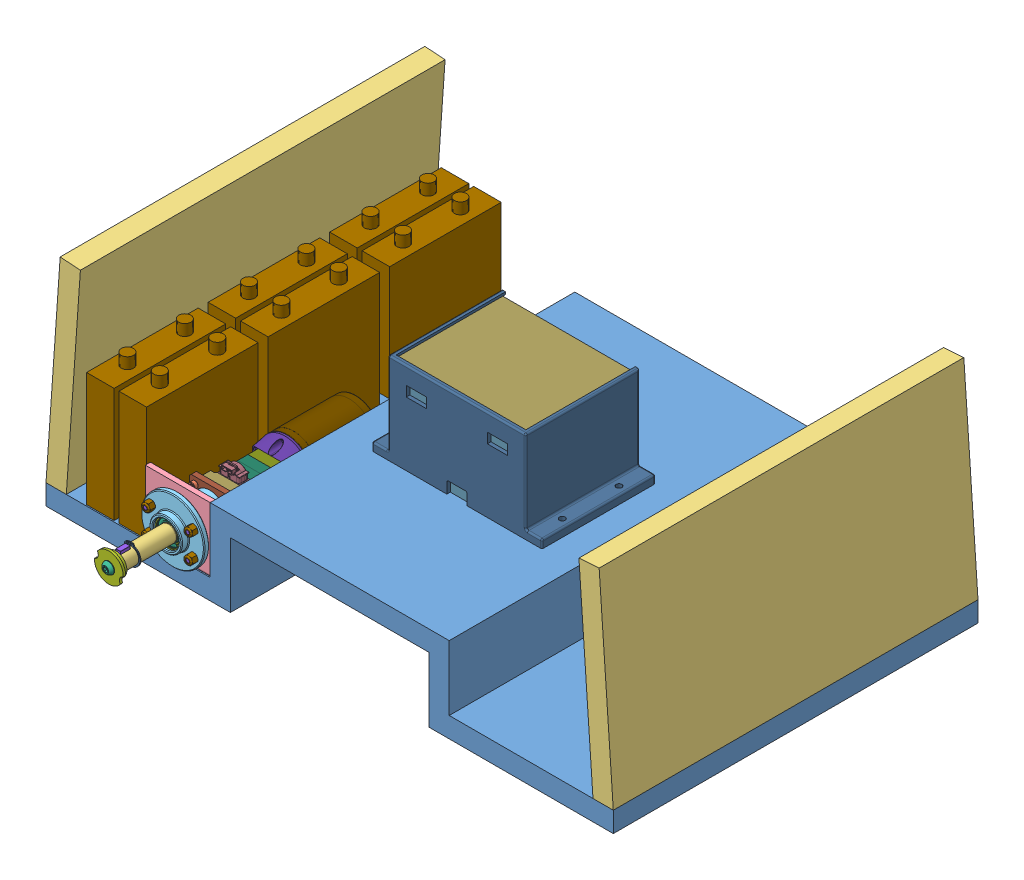
SolidWorks assembly ROVER_config2_batteries 2x3_verticales, configuration Default. Lengths in mm.
Overall size (700 275 569.67).
75 component instances, 32 part files, 13 mates.
Components (placement in the parent):
- Plancher-1: Plancher [Default] at (-314.6501 422.5882 577.2661) size (700 105 450)
- 01-Anneau_separation-1: 01-Anneau_separation [Default] at (38.152 502.5882 794.9914) x (0.982803 0 -0.184657) z (-0.184657 0 -0.982803) size (228.6 10 228.6)
- Mur_largeur-1: Mur_largeur [Default] at (-314.6501 447.5882 577.2661) size (42.42 250 450)
- Mur_largeur-2: Mur_largeur [Default] at (385.3499 447.5882 1027.2661) x (-1 0 0) z (0 0 -1) size (42.42 250 450)
- PB2023-M054 DRIVETRAIN ASSEMBLY-1: PB2023-M054 DRIVETRAIN ASSEMBLY [Default] at (-152.1501 480.5882 991.7661) x (0 1 0) z (0 0 1) size (93.83 80 344.65)
  - A12220103_FRONT_BRACKET_ASSEMBLY-1: A12220103_FRONT_BRACKET_ASSEMBLY [Default] at origin size (86 80 534.65)
    - 12220105_SUPPORT_BRACKET-1: 12220105_SUPPORT_BRACKET [Default] at (-52 -128.9256 -192.9876) x (0 0 -1) z (1 0 0) size (160.65 80 80)
    - A12220101_FRONT_CASE_ASSEMBLY-1: A12220101_FRONT_CASE_ASSEMBLY [Default] at origin size (78 78 141.2)
      - 12220103_FRONT_HOUSING-1: 12220103_FRONT_HOUSING [Default] at (-52 141.0744 -192.9876) x (0 0 -1) z (1 0 0) size (60 78 78)
      - BALL BEARING-1: BALL BEARING [6656K203] at origin size (32 32 10)
      - BALL BEARING-2: BALL BEARING [6656K203] at (0 0 41) size (32 32 10)
      - Internal Retaining Ring (98455A129)-1: Internal Retaining Ring (98455A129) [98455A129] at (0.0361 0.7992 46) x (0.998982 -0.045107 0) z (0 0 1) size (34.4 33.81 1.2)
    - M6 x 20mm Steel Hex Head Screw (91310A333)-2: M6 x 20mm Steel Hex Head Screw (91310A333) [91310A333] at (-15.125 -26.1973 37.15) x (0 0 1) z (-0.44141 0.897306 0) size (24.4 11.55 10)
    - M6 x 1mm Steel Hex LockNut (90592A016)-1: M6 x 1mm Steel Hex LockNut (90592A016) [97260A101] at (15.125 -26.1973 41.85) x (0.928554 -0.371196 0) z (-0.371196 -0.928554 0) size (10 8.38 11.55)
    - 20MM External Retaining Ring (98541A123)-4: 20MM External Retaining Ring (98541A123) [98541A123] at (0 0 92.94) x (0 0 1) z (-0.186581 0.98244 0) size (1.2 25.1 22.76)
    - A12220110_FRONT_SHAFT_ASSEMBLY-1: A12220110_FRONT_SHAFT_ASSEMBLY [Default] at (1.7896 0 -19.01) x (0 -1 0) z (0 0 1) size (78 67.32 307.03)
      - A12220105_MOTOR_BRACKET_ASSEMBLY-1: A12220105_MOTOR_BRACKET_ASSEMBLY [Default] at origin size (78 67.32 280.24) (flexible)
        - 12220106_MOTOR_BRACKET-1: 12220106_MOTOR_BRACKET [Default] at (0 -2.2046 8.53) size (78 52.48 69.85)
        - 12220106-051 MiniCIM Motor Assembly-1: 12220106-051 MiniCIM Motor Assembly [Default] at origin size (64.01 67.32 218.97)
          - Gearbox Assembly-1: Gearbox Assembly [Default] at (34.0244 -12.4567 -92.7758) x (0 0 1) z (-1 0 0) size (123.35 56.32 44.45)
            - Output Housing-2: Output Housing [Default] at (64.8023 -0.856 18.2213) x (1 0 0) z (0 -1 0) size (75.7 44.45 56.32)
              - Housing-1: Housing [Default] at (19.8785 -6.4219 -11.5232) size (18.13 44.45 42)
              - Encoder.step-1: Encoder.step [Default] at (12.6785 15.8031 -11.5232) x (0 0 1) z (-1 0 0) size (56.32 42 21.21)
              - Gearbox_output_shaft-1: Gearbox_output_shaft [Default] at origin size (63.51 17 17)
            - Ring Gears-1: Ring Gears [Default] at (71.9808 10.6671 11.7994) x (1 0 0) z (0 -1 0) size (32.2 42 42)
            - Ring Gear Stage 3-1: Ring Gear Stage 3 [Default] at (59.2808 10.6671 11.7994) x (1 0 0) z (0 -1 0) size (28.65 42 42)
          - CIM Adaptor.step-1: CIM Adaptor.step [Default] at (0 -1.7896 -68.72) x (0 -1 0) z (-1 0 0) size (64.01 21.63 64.01)
          - Mini CIM-1: Mini CIM [Default] at (0 -1.7896 -80.245) x (0 0 -1) z (1 0 0) size (101.22 64.01 64.01)
          - 8-32 X 3IN LG - Black-Oxide Alloy Steel Socket Head Screw (90044A516)-1: 8-32 X 3IN LG - Black-Oxide Alloy Steel Socket Head Screw (90044A516) [90044A516] at (17.5 15.7104 -75.245) x (-0.08536 0.99635 0) z (0 0 -1) size (6.86 6.86 81.33)
          - 8-32 X 3IN LG - Black-Oxide Alloy Steel Socket Head Screw (90044A516)-3: 8-32 X 3IN LG - Black-Oxide Alloy Steel Socket Head Screw (90044A516) [90044A516] at (-17.5 -19.2896 -75.245) x (-0.242255 0.970213 0) z (0 0 -1) size (6.86 6.86 81.33)
        - 10-32 X 0.875IN LG - Black-Oxide Alloy Steel Socket Head Screw (91251A346)-1: 10-32 X 0.875IN LG - Black-Oxide Alloy Steel Socket Head Screw (91251A346) [91251A346] at (-17.9605 16.1709 6.1805) x (0.130335 0.99147 0) z (0 0 1) size (7.94 7.94 27.67)
        - 10-32 X 0.875IN LG - Black-Oxide Alloy Steel Socket Head Screw (91251A346)-2: 10-32 X 0.875IN LG - Black-Oxide Alloy Steel Socket Head Screw (91251A346) [91251A346] at (17.9605 -19.7501 6.1805) x (0.872398 0.488796 0) z (0 0 1) size (7.94 7.94 27.67)
      - PB2023-M005 ROTARY SHAFT-1: PB2023-M005 ROTARY SHAFT [Default] at (0 -1.7896 136.57) x (0 0 -1) z (1 0 0) size (126.56 25 25)
      - 12220110_MOTOR_KEY-1: 12220110_MOTOR_KEY [Default] at (0 5.1764 16.3975) size (3.17 4.76 26.16)
    - M6 x 20mm Steel Hex Head Screw (91310A333)-7: M6 x 20mm Steel Hex Head Screw (91310A333) [91310A333] at (15.125 -26.1973 37.15) x (0 0 1) z (0.78025 0.625468 0) size (24.4 11.55 10)
    - M6 x 20mm Steel Hex Head Screw (91310A333)-9: M6 x 20mm Steel Hex Head Screw (91310A333) [91310A333] at (15.125 26.1973 37.15) x (0 0 1) z (0.877007 0.480477 0) size (24.4 11.55 10)
    - M6 x 20mm Steel Hex Head Screw (91310A333)-11: M6 x 20mm Steel Hex Head Screw (91310A333) [91310A333] at (-15.0958 26.1466 37.15) x (0 0 1) z (0.947118 0.320887 0) size (24.4 11.55 10)
    - M6 x 1mm Steel Hex LockNut (90592A016)-7: M6 x 1mm Steel Hex LockNut (90592A016) [97260A101] at (-15.125 -26.1973 41.85) x (0.975663 -0.219276 0) z (-0.219276 -0.975663 0) size (10 8.38 11.55)
    - M6 x 1mm Steel Hex LockNut (90592A016)-9: M6 x 1mm Steel Hex LockNut (90592A016) [97260A101] at (-15.125 26.1973 41.85) x (0.995642 -0.093258 0) z (-0.093258 -0.995642 0) size (10 8.38 11.55)
    - M6 x 1mm Steel Hex LockNut (90592A016)-11: M6 x 1mm Steel Hex LockNut (90592A016) [97260A101] at (15.2049 26.151 41.85) x (1 -0.000046 0) z (-0.000046 -1 0) size (10 8.38 11.55)
  - M6 x 25mm Steel Socket Head Screw (91290A330)-1: M6 x 25mm Steel Socket Head Screw (91290A330) [91290A330] at (-31.155 30 -64.48) x (0 -0.901175 -0.433456) z (1 0 0) size (10 10 31.46)
  - M6 x 25mm Steel Socket Head Screw (91290A330)-2: M6 x 25mm Steel Socket Head Screw (91290A330) [91290A330] at (-31.155 -30 -64.48) x (0 -0.15786 -0.987461) z (1 0 0) size (10 10 31.46)
  - M6 x 1mm Steel Hex LockNut (90592A016)-1: M6 x 1mm Steel Hex LockNut (90592A016) [97260A101] at (-33 -30 -64.48) x (0 0.608626 0.793457) z (0 -0.793457 0.608626) size (10 8.38 11.55)
  - M6 x 1mm Steel Hex LockNut (90592A016)-2: M6 x 1mm Steel Hex LockNut (90592A016) [97260A101] at (-33 30 -64.48) x (0 -0.994883 0.101031) z (0 -0.101031 -0.994883) size (10 8.38 11.55)
  - M8 X 20MM - 18-8 Stainless Steel Button Head Hex Drive Screws (97763A444)-1: M8 X 20MM - 18-8 Stainless Steel Button Head Hex Drive Screws (97763A444) [97763A444] at (0 0 124.825) x (0.999813 0.019347 0) z (0 0 1) size (14 14 25.15)
  - PB2023-M006 WHEEL END CAP CUSTOM WASHER-1: PB2023-M006 WHEEL END CAP CUSTOM WASHER [Default] at (0 0 117.56) x (0 0 -1) z (-0.345262 -0.938506 0) size (8.5 35.5 34.05)
  - 98870A743_Machine Key-1: 98870A743_Machine Key [98870A743] at (10 0 103.06) size (6 6 12)
- 02-Batterie-4: 02-Batterie [Default] at (-192.1501 447.5882 1025.7335) x (0 0 -1) z (1 0 0) size (137.7 155.1 34)
- A12220113_ELECTRICAL_CONTROL_BOX-1: A12220113_ELECTRICAL_CONTROL_BOX [Default] at (-17.8776 469.5906 631.9499) size (210 113.22 141.5)
  - 12220118_ELECTRICAL_BOX-1: 12220118_ELECTRICAL_BOX [Default] at (-29.7877 57.9976 190.2575) size (210 112.5 140)
  - 12220120_ELECTRICAL_BOX_OPENING_SLOT-1: 12220120_ELECTRICAL_BOX_OPENING_SLOT [Default] at (55.2123 57.9976 102.7575) x (-1 0 0) z (0 0 -1) size (30.6 54.5 6.5)
  - 12220119_ACRYLIC_SHEET-1: 12220119_ACRYLIC_SHEET [Default] at (55.2123 163.7976 170.2575) x (0 0 -1) z (1 0 0) size (135 2.8 165)
  - A12220112_SLOT_WITH_BRUSH-1: A12220112_SLOT_WITH_BRUSH [Default] at (-16.3066 139.0751 243.5929) x (0 0 -1) z (1 0 0) size (9.7 29.24 29.5)
    - 12220122_SLOT-1: 12220122_SLOT [Default] at (12.7854 19.2475 6.7689) size (9.7 11.4 29.5)
    - 12220121_BRUSH-1: 12220121_BRUSH [74405T911] at (9.9542 14.2475 21.5369) size (4.76 25.4 29.46)
  - A12220112_SLOT_WITH_BRUSH-2: A12220112_SLOT_WITH_BRUSH [Default] at (83.6934 139.0751 243.5929) x (0 0 -1) z (1 0 0) size (9.7 29.24 29.5)
    - 12220122_SLOT-1: 12220122_SLOT [Default] at (12.7854 19.2475 6.7689) size (9.7 11.4 29.5)
    - 12220121_BRUSH-1: 12220121_BRUSH [74405T911] at (9.9542 14.2475 21.5369) size (4.76 25.4 29.46)
  - A12220112_SLOT_WITH_BRUSH-3: A12220112_SLOT_WITH_BRUSH [Default] at (33.6934 62.8751 243.5929) x (0 0 -1) z (1 0 0) size (9.7 29.24 29.5)
    - 12220122_SLOT-1: 12220122_SLOT [Default] at (12.7854 19.2475 6.7689) size (9.7 11.4 29.5)
    - 12220121_BRUSH-1: 12220121_BRUSH [74405T911] at (9.9542 14.2475 21.5369) size (4.76 25.4 29.46)
  - A12220112_SLOT_WITH_BRUSH-4: A12220112_SLOT_WITH_BRUSH [Default] at (26.7312 139.0751 96.9221) x (0 0 1) z (-1 0 0) size (9.7 29.24 29.5)
    - 12220122_SLOT-1: 12220122_SLOT [Default] at (12.7854 19.2475 6.7689) size (9.7 11.4 29.5)
    - 12220121_BRUSH-1: 12220121_BRUSH [74405T911] at (9.9542 14.2475 21.5369) size (4.76 25.4 29.46)
  - A12220112_SLOT_WITH_BRUSH-5: A12220112_SLOT_WITH_BRUSH [Default] at (126.7312 139.0751 96.9221) x (0 0 1) z (-1 0 0) size (9.7 29.24 29.5)
    - 12220122_SLOT-1: 12220122_SLOT [Default] at (12.7854 19.2475 6.7689) size (9.7 11.4 29.5)
    - 12220121_BRUSH-1: 12220121_BRUSH [74405T911] at (9.9542 14.2475 21.5369) size (4.76 25.4 29.46)
  - A12220112_SLOT_WITH_BRUSH-6: A12220112_SLOT_WITH_BRUSH [Default] at (76.7312 117.8751 96.9221) x (0 0 1) z (-1 0 0) size (9.7 29.24 29.5)
    - 12220122_SLOT-1: 12220122_SLOT [Default] at (12.7854 19.2475 6.7689) size (9.7 11.4 29.5)
    - 12220121_BRUSH-1: 12220121_BRUSH [74405T911] at (9.9542 14.2475 21.5369) size (4.76 25.4 29.46)
- 02-Batterie-5: 02-Batterie [Default] at (-232.1501 447.5882 1025.7335) x (0 0 -1) z (1 0 0) size (137.7 155.1 34)
- 02-Batterie-6: 02-Batterie [Default] at (-192.1501 447.5882 875.7335) x (0 0 -1) z (1 0 0) size (137.7 155.1 34)
- 02-Batterie-7: 02-Batterie [Default] at (-232.1501 447.5882 875.7335) x (0 0 -1) z (1 0 0) size (137.7 155.1 34)
- 02-Batterie-8: 02-Batterie [Default] at (-192.1501 447.5882 725.7335) x (0 0 -1) z (1 0 0) size (137.7 155.1 34)
- 02-Batterie-9: 02-Batterie [Default] at (-232.1501 447.5882 725.7335) x (0 0 -1) z (1 0 0) size (137.7 155.1 34)
Mates (geometry in assembly coordinates):
- Coincident5: coincident anti-aligned: plane of Plancher-1 through (-87.1501 502.5882 1027.2661) normal (0 -1 0); plane of 01-Anneau_separation-1 through (38.152 502.5882 794.9914) normal (0 1 0)
- Coincident6: coincident anti-aligned: plane of Plancher-1 through (-314.6501 447.5882 1027.2661) normal (0 1 0); plane of Mur_largeur-1 through (-289.5891 447.5882 1027.2661) normal (0 -1 0)
- Coincident7: coincident aligned: plane of Plancher-1 through (-314.6501 422.5882 1027.2661) normal (0 0 1); plane of Mur_largeur-1 through (-314.6501 447.5882 1027.2661) normal (0 0 1)
- Coincident8: coincident aligned: line of Plancher-1 through (-314.6501 447.5882 1027.2661) axis (0 0 -1); line of Mur_largeur-1 through (-314.6501 447.5882 1027.2661) axis (0 0 -1)
- Coincident9: coincident anti-aligned: plane of Plancher-1 through (385.3499 447.5882 1027.2661) normal (0 1 0); plane of Mur_largeur-2 through (360.2888 447.5882 577.2661) normal (0 -1 0)
- Coincident10: coincident aligned: plane of Plancher-1 through (-314.6501 422.5882 1027.2661) normal (0 0 1); plane of Mur_largeur-2 through (385.3499 447.5882 1027.2661) normal (0 0 1)
- Coincident11: coincident anti-aligned: line of Plancher-1 through (385.3499 447.5882 1027.2661) axis (0 0 -1); line of Mur_largeur-2 through (385.3499 447.5882 577.2661) axis (0 0 1)
- Coincident12: coincident anti-aligned: plane of Plancher-1 through (-314.6501 447.5882 1027.2661) normal (0 1 0); plane of PB2023-M054 DRIVETRAIN ASSEMBLY-1/A12220103_FRONT_BRACKET_ASSEMBLY-1/12220105_SUPPORT_BRACKET-1 through (-152.1501 447.5882 1027.2661) normal (0 -1 0)
- Coincident13: coincident aligned: plane of Plancher-1 through (-314.6501 422.5882 1027.2661) normal (0 0 1); plane of PB2023-M054 DRIVETRAIN ASSEMBLY-1/A12220103_FRONT_BRACKET_ASSEMBLY-1/12220105_SUPPORT_BRACKET-1 through (-192.1501 453.9382 1027.2661) normal (0 0 1)
- Coincident14: coincident anti-aligned: plane of Plancher-1 through (-112.1501 447.5882 1027.2661) normal (-1 0 0); plane of PB2023-M054 DRIVETRAIN ASSEMBLY-1/A12220103_FRONT_BRACKET_ASSEMBLY-1/12220105_SUPPORT_BRACKET-1 through (-112.1501 453.9382 1027.2661) normal (1 0 0)
- Coincident21: coincident anti-aligned: plane of Plancher-1 through (-112.1501 527.5882 1027.2661) normal (0 1 0); plane of A12220113_ELECTRICAL_CONTROL_BOX-1/12220118_ELECTRICAL_BOX-1 through (122.3347 527.5882 822.2073) normal (0 -1 0)
- Coincident22: coincident anti-aligned: plane of PB2023-M054 DRIVETRAIN ASSEMBLY-1/A12220103_FRONT_BRACKET_ASSEMBLY-1/12220105_SUPPORT_BRACKET-1 through (-192.1501 453.9382 831.6161) normal (-1 0 0); plane of 02-Batterie-4 through (-192.1501 588.8882 1025.7335) normal (1 0 0)
- Coincident23: coincident anti-aligned: plane of Plancher-1 through (-314.6501 447.5882 1027.2661) normal (0 1 0); plane of 02-Batterie-4 through (-192.1501 447.5882 1025.7335) normal (0 -1 0)
